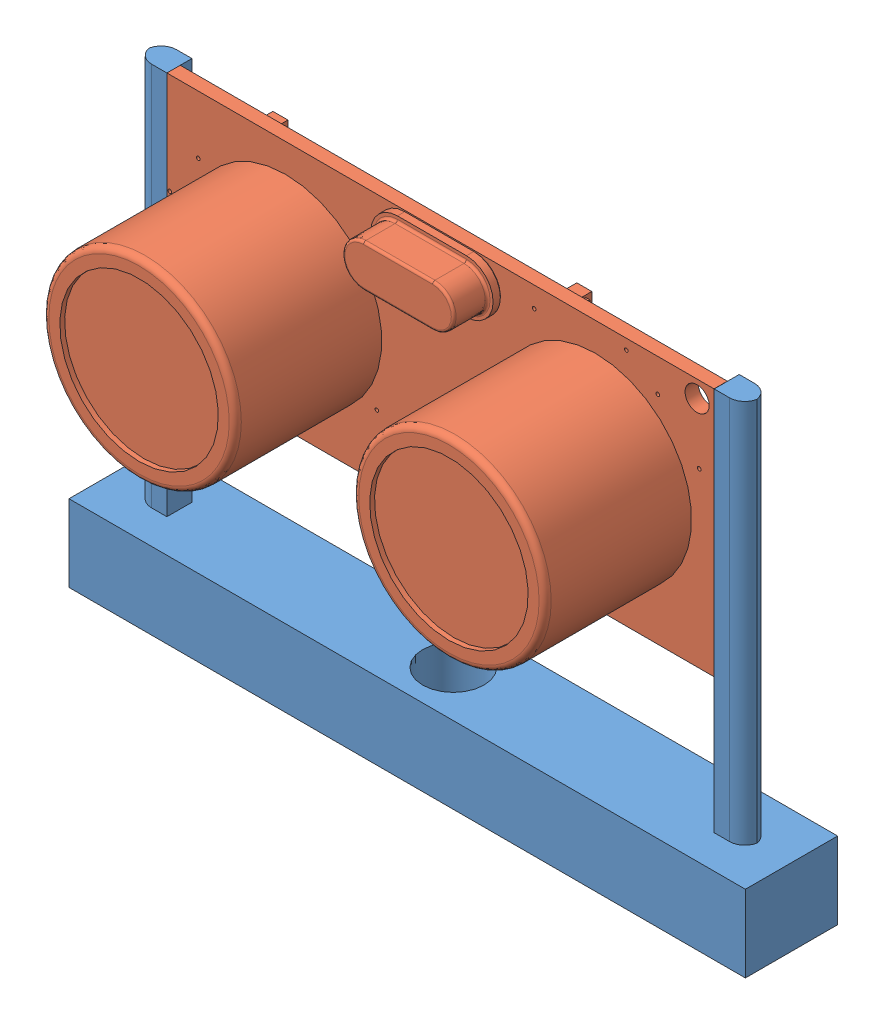
SolidWorks assembly Sensor Assembly, configuration Default. Lengths in mm.
Overall size (55.88 38.1 18.55).
2 component instances, 2 part files, 4 mates.
Components (placement in the parent):
- Sensor Base-1: Sensor Base [Default] at (34.3289 22.119 46.0135) size (55.88 38.1 7.62)
- Distance Sensor-1: Distance Sensor [Detailed] at (34.3229 46.744 49.7785) x (1 0 0) z (0 -1 0) size (45.2 18.55 25.75)
Mates (geometry in assembly coordinates):
- Parallel1: parallel aligned: plane of Sensor Base-1 through (34.3289 22.119 53.6335) normal (0 0 1); plane of Distance Sensor-1 through (34.3229 46.744 50.8785) normal (0 0 1)
- Parallel2: parallel aligned: plane of Sensor Base-1 through (6.3889 18.944 53.6335) normal (-1 0 0); plane of Distance Sensor-1 through (11.7229 36.444 50.8785) normal (-1 0 0)
- Coincident7: coincident aligned: line of Sensor Base-1 through (11.7229 57.044 50.8785) axis (0 -1 0); line of Distance Sensor-1 through (11.7229 57.044 50.8785) axis (0 -1 0)
- Coincident8: coincident aligned: plane of Sensor Base-1 through (34.3289 57.044 46.0135) normal (0 1 0); plane of Distance Sensor-1 through (56.9229 57.044 50.8785) normal (0 1 0)
